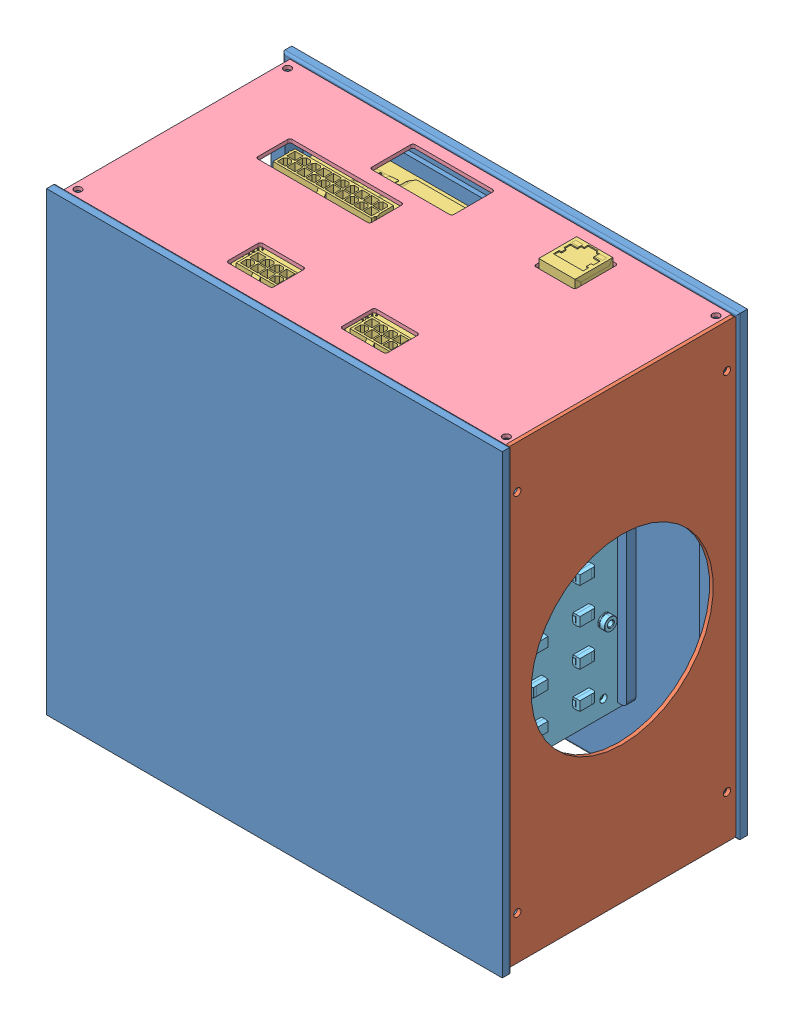
SolidWorks assembly Assemblage EKO_Miner box V3, configuration Défaut. Lengths in mm.
Overall size (200.4 201.3 113.9).
14 component instances, 8 part files, 33 mates.
Components (placement in the parent):
- Case - BottomTop 200x200-1: Case - BottomTop 200x200 [Défaut] at (-119.8446 -102.7042 220) size (200 200 12)
- Case - Coté-1: Case - Coté [Défaut] at (-116.3513 96.2958 224) x (0 -1 0) z (-1 0 0) size (198 100 1.6) (hidden)
- Case - Coté-2: Case - Coté [Défaut] at (77.5554 -101.7042 224) x (0 1 0) z (1 0 0) size (198 100 1.6)
- Case - BottomTop 200x200-2: Case - BottomTop 200x200 [Défaut] at (80.5554 -102.7042 328) x (-1 0 0) z (0 0 -1) size (200 200 12)
- EKO_MyMiner-1: EKO_MyMiner [Défaut] at (-168.0766 81.2958 364.132) x (1 0 0) z (0 -1 0) size (140 100 29.95)
- Case - Rear-1: Case - Rear [Défaut] at (77.3554 94.2958 224) x (-1 0 0) z (0 1 0) size (194 100 1.6)
- EKO_Miner_BM1366 BM13xx-16 01A-2: EKO_Miner_BM1366 BM13xx-16 01A [Défaut] at (30.7554 139.4458 348.8) x (0 -1 0) z (-1 0 0) size (148.4 99.75 14.93)
- EKO_Miner_BM1366 BM13xx-16 01A HEATSINK-1: EKO_Miner_BM1366 BM13xx-16 01A HEATSINK [Défaut] at (25.6554 139.4458 348.8) x (0 -1 0) z (-1 0 0) size (153.61 113.9 8)
- CHC3 M3x6mm-1: CHC3 M3x6mm [M3X6mm] at (25.7554 -47.5542 234.8) x (0 0.991709 0.128504) z (1 0 0) size (5.5 5.5 9.19)
- CHC3 M3x6mm-2: CHC3 M3x6mm [M3X6mm] at (25.7554 32.4458 234.8) x (0 0.168282 -0.985739) z (1 0 0) size (5.5 5.5 9.19)
- CHC3 M3x6mm-3: CHC3 M3x6mm [M3X6mm] at (33.7554 -68.5542 274.8) x (0 -0.924225 -0.381849) z (1 0 0) size (5.5 5.5 9.19)
- CHC3 M3x6mm-4: CHC3 M3x6mm [M3X6mm] at (33.7554 53.4458 274.8) x (0 -0.951548 -0.307499) z (1 0 0) size (5.5 5.5 9.19)
- BarBus 40.5mm-1: BarBus 40.5mm [Défaut] at (34.0354 27.4458 229.8) x (0 0 1) z (1 0 0) size (48.5 8 2)
- CHC3 M3x6mm-5: CHC3 M3x6mm [M3X6mm] at (39.0354 23.4458 274.3) x (0 0.990457 -0.137825) z (1 0 0) size (5.5 5.5 9.19)
Mates (geometry in assembly coordinates):
- Coïncidente8: coincident anti-aligned: plane of Case - BottomTop 200x200-1 through (-110.8446 81.2958 232) normal (0 -1 0); plane of PCB fond panier-1 through (-89.8446 101.2958 224) normal (0 1 0)
- Coïncidente9: coincident anti-aligned: plane of PCB fond panier-1 through (-89.8446 99.6958 224) normal (0 -1 0); plane of 10018784-10210TLF--3DModel-STEP-56544-1 through (27.1485 99.6958 299.4976) normal (0 1 0)
- Parallèle1: parallel aligned: plane of PCB fond panier-1 through (-89.8446 99.6958 324) normal (0 0 1); plane of 10018784-10210TLF--3DModel-STEP-56544-1 through (25.4457 98.8858 301.5344) normal (0 0 1)
- Coaxiale1: concentric aligned: circle of Case - Bottom-1; circle of PCB fond panier-1
- Coaxiale2: concentric aligned: cylinder of Case - BottomTop 200x200-1 through (45.1554 91.2958 228) axis (0 -1 0) radius 1.6; cylinder of PCB fond panier-1 through (45.1554 101.2958 228) axis (0 -1 0) radius 1.6
- Coaxiale10: concentric anti-aligned: circle of Case - Coté-2; circle of Case - BottomTop-2
- Coaxiale14: concentric anti-aligned: cylinder of Case - BottomTop 200x200-1 through (67.1554 77.2958 228) axis (1 0 0) radius 1.6; cylinder of Case - Coté-2 through (79.1554 77.2958 228) axis (-1 0 0) radius 1.6
- Coaxiale15: concentric anti-aligned: cylinder of Case - BottomTop 200x200-1 through (-106.8446 -82.7042 228) axis (-1 0 0) radius 1.6; cylinder of Case - Coté-1 through (-117.9513 -82.7042 228) axis (1 0 0) radius 1.6
- Coaxiale16: concentric anti-aligned: cylinder of Case - Coté-2 through (79.1554 77.2958 320) axis (-1 0 0) radius 1.6; cylinder of Case - BottomTop 200x200-2 through (67.5554 77.2958 320) axis (1 0 0) radius 1.6
- Coaxiale17: concentric anti-aligned: cylinder of Case - BottomTop 200x200-1 through (67.1554 -82.7042 228) axis (1 0 0) radius 1.6; cylinder of Case - Coté-2 through (79.1554 -82.7042 228) axis (-1 0 0) radius 1.6
- Coïncidente17: coincident anti-aligned: plane of Case - Coté-2 through (77.5554 95.2958 323) normal (-1 0 0); plane of Case - BottomTop 200x200-2 through (77.5554 94.2958 316) normal (1 0 0)
- Coaxiale18: concentric anti-aligned: cylinder of Case - BottomTop 200x200-1 through (-106.8446 77.2958 228) axis (-1 0 0) radius 1.6; cylinder of Case - Coté-1 through (-117.9513 77.2958 228) axis (1 0 0) radius 1.6
- Coaxiale21: concentric aligned: cylinder of Case - BottomTop 200x200-2 through (-113.6446 84.2958 320) axis (0 1 0) radius 1.6; cylinder of Case - Rear-1 through (-113.6446 94.2958 320) axis (0 1 0) radius 1.6
- Coaxiale22: concentric aligned: cylinder of Case - BottomTop 200x200-1 through (74.3554 84.2958 228) axis (0 1 0) radius 1.6; cylinder of Case - Rear-1 through (74.3554 94.2958 228) axis (0 1 0) radius 1.6
- Coïncidente20: coincident anti-aligned: plane of Case - BottomTop 200x200-2 through (-116.4446 94.2958 316) normal (0 1 0); plane of Case - Rear-1 through (77.3554 94.2958 224) normal (0 -1 0)
- Distance1: distance = 0.1 mm anti-aligned: plane of EKO_Miner_BM1366 BM13xx-16 01A-2 through (29.1554 3.8739 276.3972) normal (-1 0 0); plane of Case - BottomTop 200x200-1 through (29.2554 72.2958 232) normal (1 0 0)
- Distance2: distance = 0.2 mm anti-aligned: plane of Case - BottomTop 200x200-1 through (-119.8446 -102.7042 224) normal (0 0 1); plane of EKO_Miner_BM1366 BM13xx-16 01A-2 through (30.7554 -75.3042 223.8) normal (0 0 -1)
- Distance3: distance = 15 mm anti-aligned: plane of EKO_Miner_BM1366 BM13xx-16 01A-2 through (30.7554 64.6958 223.8) normal (0 1 0); plane of EKO_MyMiner-1 through (-19.8446 79.6958 274) normal (0 -1 0)
- Coaxiale23: concentric anti-aligned: cylinder of Case - BottomTop 200x200-1 through (45.1554 91.2958 228) axis (0 -1 0) radius 1.6; cylinder of EKO_MyMiner-1 through (45.1554 81.3408 228) axis (0 1 0) radius 1.6
- Parallèle2: parallel anti-aligned: cylinder of Case - BottomTop 200x200-2 through (-84.4446 91.2958 320) axis (0 -1 0) radius 1.6; cylinder of EKO_MyMiner-1 through (-84.8446 81.3408 320) axis (0 1 0) radius 1.6
- Coïncidente24: coincident anti-aligned: plane of Case - BottomTop 200x200-2 through (71.5554 81.2958 316) normal (0 -1 0); plane of EKO_MyMiner-1 through (-19.8446 81.2958 274) normal (0 1 0)
- Coaxiale24: concentric aligned: cylinder of EKO_Miner_BM1366 BM13xx-16 01A-2 through (30.8004 -68.5542 297.8) axis (1 0 0) radius 1.6; cylinder of EKO_Miner_BM1366 BM13xx-16 01A HEATSINK-1 through (29.1554 -68.5542 297.8) axis (1 0 0) radius 1.25
- Coaxiale25: concentric aligned: cylinder of EKO_Miner_BM1366 BM13xx-16 01A-2 through (30.8004 53.4458 233.8) axis (1 0 0) radius 1.6; cylinder of EKO_Miner_BM1366 BM13xx-16 01A HEATSINK-1 through (29.1554 53.4458 233.8) axis (1 0 0) radius 1.25
- Coïncidente25: coincident anti-aligned: plane of EKO_Miner_BM1366 BM13xx-16 01A-2 through (29.1554 3.8739 276.3972) normal (-1 0 0); plane of EKO_Miner_BM1366 BM13xx-16 01A HEATSINK-1 through (29.1554 53.4458 233.8) normal (1 0 0)
- Coaxiale29: concentric aligned: cylinder of EKO_Miner_BM1366 BM13xx-16 01A-2 through (30.8004 -68.5542 274.8) axis (1 0 0) radius 1.6; cylinder of CHC3 M3x6mm-3 through (33.7554 -68.5542 274.8) axis (1 0 0) radius 1.5
- Coïncidente30: coincident anti-aligned: plane of EKO_Miner_BM1366 BM13xx-16 01A-2 through (30.7554 3.8739 276.3972) normal (1 0 0); plane of CHC3 M3x6mm-3 through (30.7554 -67.5862 272.4571) normal (-1 0 0)
- Coaxiale30: concentric aligned: cylinder of EKO_Miner_BM1366 BM13xx-16 01A-2 through (30.8004 53.4458 274.8) axis (1 0 0) radius 1.6; cylinder of CHC3 M3x6mm-4 through (33.7554 53.4458 274.8) axis (1 0 0) radius 1.5
- Coïncidente31: coincident anti-aligned: plane of EKO_Miner_BM1366 BM13xx-16 01A-2 through (30.7554 3.8739 276.3972) normal (1 0 0); plane of CHC3 M3x6mm-4 through (30.7554 54.2253 272.3878) normal (-1 0 0)
- Coaxiale31: concentric anti-aligned: cylinder of EKO_Miner_BM1366 BM13xx-16 01A-2 through (31.7704 23.4458 274.3) axis (-1 0 0) radius 1.2295; circle of BarBus 40.5mm-1
- Coaxiale32: concentric aligned: cylinder of EKO_Miner_BM1366 BM13xx-16 01A-2 through (31.7704 23.4458 233.8) axis (-1 0 0) radius 1.2295; cylinder of BarBus 40.5mm-1 through (36.0354 23.4458 233.8) axis (-1 0 0) radius 1.6
- Coïncidente32: coincident anti-aligned: plane of EKO_Miner_BM1366 BM13xx-16 01A-2 through (34.0354 24.7941 274.3) normal (1 0 0); plane of BarBus 40.5mm-1 through (34.0354 23.4458 233.8) normal (-1 0 0)
- Coaxiale33: concentric anti-aligned: cylinder of BarBus 40.5mm-1 through (36.0354 23.4458 274.3) axis (-1 0 0) radius 1.6; cylinder of CHC3 M3x6mm-5 through (39.0354 23.4458 274.3) axis (1 0 0) radius 1.5
- Coïncidente33: coincident anti-aligned: plane of BarBus 40.5mm-1 through (36.0354 23.4458 233.8) normal (1 0 0); plane of CHC3 M3x6mm-5 through (36.0354 23.7952 276.8108) normal (-1 0 0)
